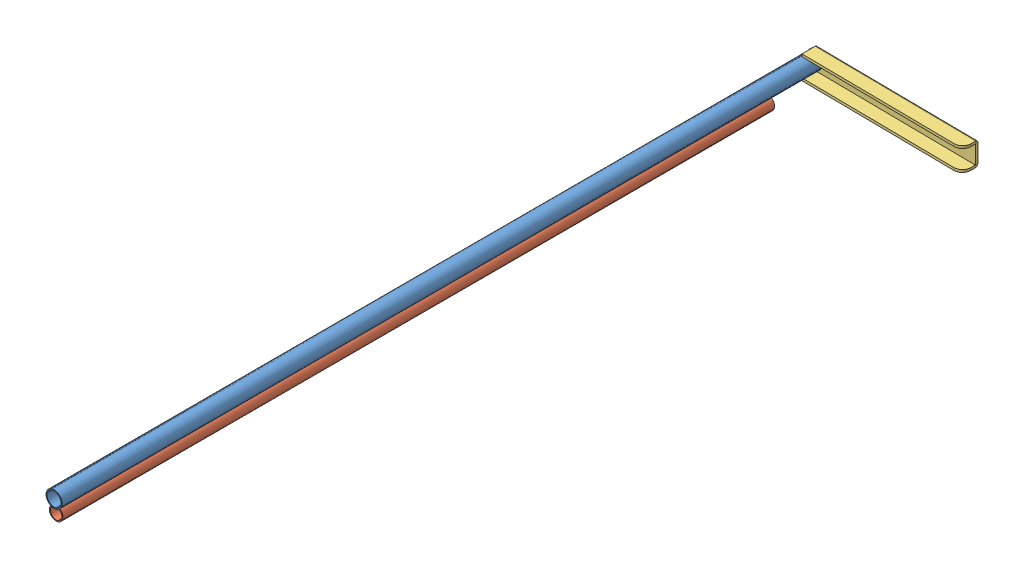
SolidWorks assembly 軌道凸輪把手-2, configuration 預設. Lengths in mm.
Overall size (202.29 41.96 903).
3 component instances, 3 part files, 4 mates.
Components (placement in the parent):
- LB-A54-12-13-1: LB-A54-12-13 [預設] at (-5715.213 -6060.6023 -450) size (19.02 19.02 900)
- LB-A54-12-14-1: LB-A54-12-14 [預設] at (-53311.4351 -141278.0126 -396) x (0.413833 0.910353 0) z (0 0 1) size (16 16 842)
- LB-A54-12-11-1: LB-A54-12-11 [預設] at (-20.8356 -11.3744 -453) x (0.99994 -0.010955 0) z (0 0 1) size (200 27.64 18.32)
Mates (geometry in assembly coordinates):
- 相切1: tangent anti-aligned: cylinder of LB-A54-12-13-1 through (-10.5437 15.2144 450) axis (0 0 -1) radius 9.51; cylinder of LB-A54-12-14-1 through (-12.0993 -2.2263 446) axis (0 0 -1) radius 8
- 平行相距1: distance = 4 mm aligned: plane of LB-A54-12-13-1 through (-10.5437 15.2144 450) normal (0 0 1); plane of LB-A54-12-14-1 through (-12.0993 -2.2263 446) normal (0 0 1)
- 重合/共線/共點3: coincident: plane of LB-A54-12-13-1 through (-10.5437 15.2144 -450) normal (0 0 -1); plane of LB-A54-12-11-1 through (-10.5437 15.2144 -450) normal (0 0 1)
- 同軸心2: concentric aligned: cylinder of LB-A54-12-13-1 through (-10.5437 15.2144 450) axis (0 0 -1) radius 9.51; cylinder of LB-A54-12-11-1 through (-10.5437 15.2144 -450) axis (0 0 -1) radius 10
